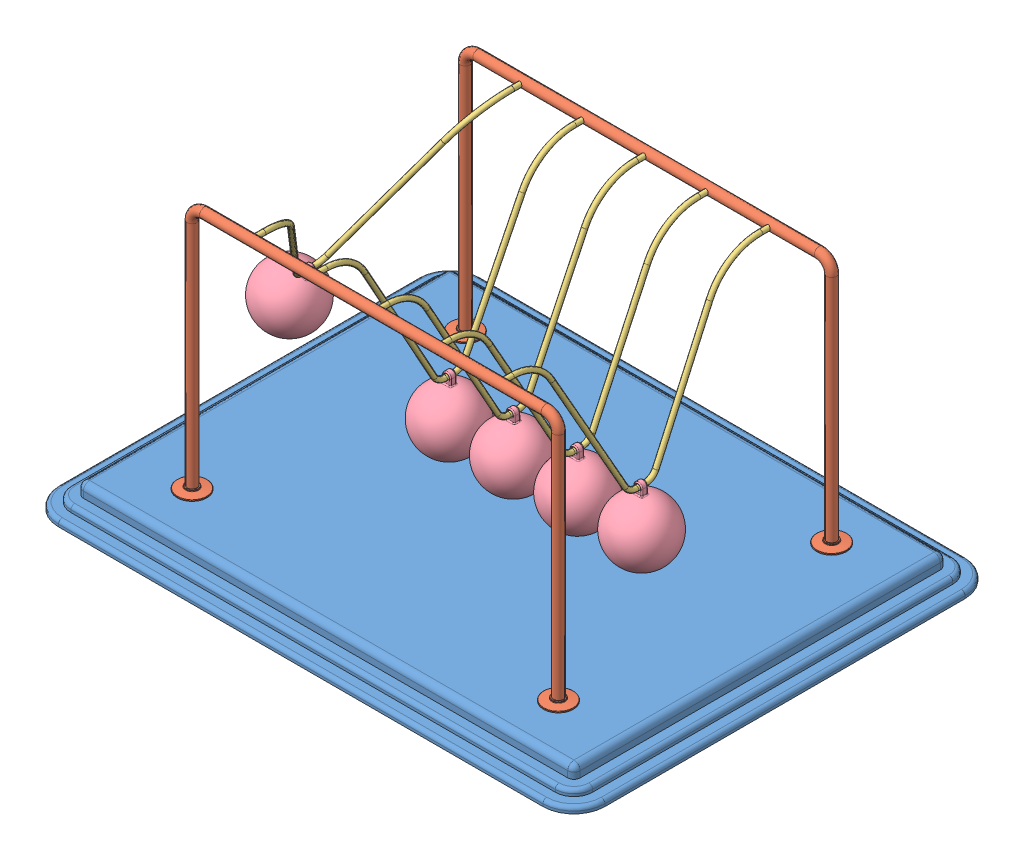
SolidWorks assembly Newtons Cradle NewtonsCradle 0238, configuration Default. Lengths in mm.
Overall size (440 222 340).
13 component instances, 4 part files, 34 mates.
Components (placement in the parent):
- Base NewtonsCradle 0238-1: Base NewtonsCradle 0238 [Default] at (-16.2968 -4.1587 11.425) size (440 20 340)
- frame NewtonsCradle 0238-1: frame NewtonsCradle 0238 [Default] at (-16.2968 144.4547 -98.575) size (319 202 24)
- frame NewtonsCradle 0238-2: frame NewtonsCradle 0238 [Default] at (-16.2968 144.4547 121.425) x (-1 0 0) z (0 0 -1) size (319 202 24)
- Hanging thing NewtonsCradle 0238-1: Hanging thing NewtonsCradle 0238 [Default] at (-157.6326 134.1825 11.425) x (0 0 1) z (-0.859985 0.510319 0) size (220 129 4)
- Hanging thing NewtonsCradle 0238-2: Hanging thing NewtonsCradle 0238 [Default] at (-66.576 122.8418 11.425) x (0 0 1) z (-0.999994 0.003446 0) size (220 129 4)
- Hanging thing NewtonsCradle 0238-3: Hanging thing NewtonsCradle 0238 [Default] at (-15.6923 122.8436 11.425) x (0 0 1) z (-0.999972 -0.007464 0) size (220 129 4)
- Hanging thing NewtonsCradle 0238-4: Hanging thing NewtonsCradle 0238 [Default] at (35.2213 122.8555 11.425) x (0 0 1) z (-0.999824 -0.018742 0) size (220 129 4)
- Hanging thing NewtonsCradle 0238-5: Hanging thing NewtonsCradle 0238 [Default] at (86.0287 122.8747 11.425) x (0 0 1) z (-0.999588 -0.028711 0) size (220 129 4)
- Sphere NewtonsCradle 0238-1: Sphere NewtonsCradle 0238 [Default] at (-195.3962 70.5436 11.425) x (0.859985 -0.510319 0) z (0 0 1) size (50 58.5 50)
- Sphere NewtonsCradle 0238-2: Sphere NewtonsCradle 0238 [Default] at (88.1533 48.9052 11.425) x (0.999588 0.028711 0) z (0 0 1) size (50 58.5 50)
- Sphere NewtonsCradle 0238-3: Sphere NewtonsCradle 0238 [Default] at (-15.14 48.8456 11.425) x (0.999972 0.007464 0) z (0 0 1) size (50 58.5 50)
- Sphere NewtonsCradle 0238-4: Sphere NewtonsCradle 0238 [Default] at (36.6081 48.8685 11.425) x (0.999824 0.018742 0) z (0 0 1) size (50 58.5 50)
- Sphere NewtonsCradle 0238-5: Sphere NewtonsCradle 0238 [Default] at (-66.831 48.8422 11.425) x (0.999994 -0.003446 0) z (0 0 1) size (50 58.5 50)
Mates (geometry in assembly coordinates):
- Coincident1: coincident anti-aligned: plane of Base-1 through (-211.2968 5.8413 156.425) normal (0 1 0); plane of frame-2 through (-175.7968 5.8413 121.425) normal (0 -1 0)
- Coincident2: coincident anti-aligned: plane of Base-1 through (-211.2968 5.8413 156.425) normal (0 1 0); plane of frame-1 through (143.2032 5.8413 -98.575) normal (0 -1 0)
- Concentric1: concentric anti-aligned: cylinder of frame-1 through (-116.2968 203.8413 -94.575) axis (0 0 -1) radius 2; cylinder of frame-2 through (-116.2968 203.8413 117.425) axis (0 0 1) radius 2
- Concentric2: concentric anti-aligned: cylinder of frame-1 through (83.7032 203.8413 -94.575) axis (0 0 -1) radius 2; cylinder of frame-2 through (83.7032 203.8413 117.425) axis (0 0 1) radius 2
- Distance1: distance = 60 mm: plane of frame-1 through (-16.2968 144.4547 -98.575) normal (0 0 1); line of Base-1 through (-211.2968 -12.1587 -158.575) axis (1 0 0)
- Distance2: distance = 60 mm: line of Base-1 through (178.7032 -12.1587 181.425) axis (-1 0 0); plane of frame-2 through (-16.2968 144.4547 121.425) normal (0 0 -1)
- Distance3: distance = 220 mm: plane of frame-2 through (-16.2968 144.4547 121.425) normal (-1 0 0); line of Base-1 through (-236.2968 -12.1587 156.425) axis (0 0 -1)
- Concentric3: concentric anti-aligned: cylinder of frame-1 through (-116.2968 203.8413 -94.575) axis (0 0 -1) radius 2; cylinder of Hanging thing-1 through (-116.2968 203.8413 111.425) axis (0 0 1) radius 2
- Concentric4: concentric anti-aligned: cylinder of frame-1 through (-116.2968 203.8413 -94.575) axis (0 0 -1) radius 2; cylinder of Hanging thing-1 through (-116.2968 203.8413 -98.575) axis (0 0 1) radius 2
- Concentric5: concentric aligned: cylinder of frame-2 through (-66.2968 203.8413 117.425) axis (0 0 1) radius 2; cylinder of Hanging thing-2 through (-66.2968 203.8413 111.425) axis (0 0 1) radius 2
- Concentric6: concentric aligned: cylinder of frame-2 through (-16.2968 203.8413 117.425) axis (0 0 1) radius 2; cylinder of Hanging thing-3 through (-16.2968 203.8413 111.425) axis (0 0 1) radius 2
- Concentric7: concentric aligned: cylinder of frame-2 through (33.7032 203.8413 117.425) axis (0 0 1) radius 2; cylinder of Hanging thing-4 through (33.7032 203.8413 111.425) axis (0 0 1) radius 2
- Concentric8: concentric aligned: cylinder of frame-2 through (83.7032 203.8413 117.425) axis (0 0 1) radius 2; cylinder of Hanging thing-5 through (83.7032 203.8413 111.425) axis (0 0 1) radius 2
- Coincident5: coincident anti-aligned: plane of frame-2 through (83.7032 203.8413 121.425) normal (0 0 -1); plane of Hanging thing-5 through (83.7032 203.8413 121.425) normal (0 0 1)
- Coincident6: coincident anti-aligned: plane of frame-2 through (33.7032 203.8413 121.425) normal (0 0 -1); plane of Hanging thing-4 through (33.7032 203.8413 121.425) normal (0 0 1)
- Coincident7: coincident anti-aligned: plane of frame-2 through (-16.2968 203.8413 121.425) normal (0 0 -1); plane of Hanging thing-3 through (-16.2968 203.8413 121.425) normal (0 0 1)
- Coincident8: coincident anti-aligned: plane of frame-2 through (-66.2968 203.8413 121.425) normal (0 0 -1); plane of Hanging thing-2 through (-66.2968 203.8413 121.425) normal (0 0 1)
- Coincident9: coincident anti-aligned: plane of frame-2 through (-116.2968 203.8413 121.425) normal (0 0 -1); plane of Hanging thing-1 through (-116.2968 203.8413 121.425) normal (0 0 1)
- Concentric9: concentric anti-aligned: cylinder of Hanging thing-1 through (-117.0163 78.8434 7.925) axis (0 0 1) radius 2; cylinder of Sphere-1 through (-117.0163 78.8434 13.925) axis (0 0 -1) radius 2
- Concentric13: concentric anti-aligned: cylinder of Hanging thing-2 through (-66.7276 78.842 7.925) axis (0 0 1) radius 2; cylinder of Sphere-5 through (-66.7276 78.842 13.925) axis (0 0 -1) radius 2
- Concentric15: concentric anti-aligned: cylinder of Hanging thing-3 through (-15.3639 78.8448 7.925) axis (0 0 1) radius 2; cylinder of Sphere-3 through (-15.3639 78.8448 13.925) axis (0 0 -1) radius 2
- Concentric16: concentric anti-aligned: cylinder of Hanging thing-5 through (87.292 78.8928 7.925) axis (0 0 1) radius 2; cylinder of Sphere-2 through (87.292 78.8928 13.925) axis (0 0 -1) radius 2
- Concentric17: concentric anti-aligned: cylinder of Hanging thing-4 through (36.0459 78.8632 7.925) axis (0 0 1) radius 2; cylinder of Sphere-4 through (36.0459 78.8632 13.925) axis (0 0 -1) radius 2
- Parallel1: parallel anti-aligned: plane of Hanging thing-1; plane of Sphere-1
- Coincident22: coincident anti-aligned: plane of Hanging thing-1; plane of Sphere-1
- Coincident12: coincident aligned: plane of Hanging thing-2 through (-66.576 122.8418 11.425) normal (0 0 1); plane of Sphere-5 through (-66.831 48.8422 11.425) normal (0 0 1)
- Coincident10: coincident aligned: plane of Hanging thing-1 through (-116.763 122.8426 11.425) normal (0 0 1); plane of Sphere-1 through (-118.5806 48.8842 11.425) normal (0 0 1)
- Coincident13: coincident anti-aligned: plane of Hanging thing-2 through (-66.576 122.8418 11.425) normal (-0.999994 0.003446 0); plane of Sphere-5 through (-66.831 48.8422 11.425) normal (0.999994 -0.003446 0)
- Coincident14: coincident anti-aligned: plane of Hanging thing-3 through (-15.6923 122.8436 11.425) normal (-0.999972 -0.007464 0); plane of Sphere-3 through (-15.14 48.8456 11.425) normal (0.999972 0.007464 0)
- Coincident15: coincident aligned: plane of Hanging thing-3 through (-15.6923 122.8436 11.425) normal (0 0 1); plane of Sphere-3 through (-15.14 48.8456 11.425) normal (0 0 1)
- Coincident18: coincident aligned: plane of Hanging thing-4 through (35.2213 122.8555 11.425) normal (0 0 1); plane of Sphere-4 through (36.6081 48.8685 11.425) normal (0 0 1)
- Coincident19: coincident anti-aligned: plane of Hanging thing-4 through (35.2213 122.8555 11.425) normal (-0.999824 -0.018742 0); plane of Sphere-4 through (36.6081 48.8685 11.425) normal (0.999824 0.018742 0)
- Coincident20: coincident anti-aligned: plane of Hanging thing-5 through (86.0287 122.8747 11.425) normal (-0.999588 -0.028711 0); plane of Sphere-2 through (88.1533 48.9052 11.425) normal (0.999588 0.028711 0)
- Coincident21: coincident aligned: plane of Hanging thing-5 through (86.0287 122.8747 11.425) normal (0 0 1); plane of Sphere-2 through (88.1533 48.9052 11.425) normal (0 0 1)
